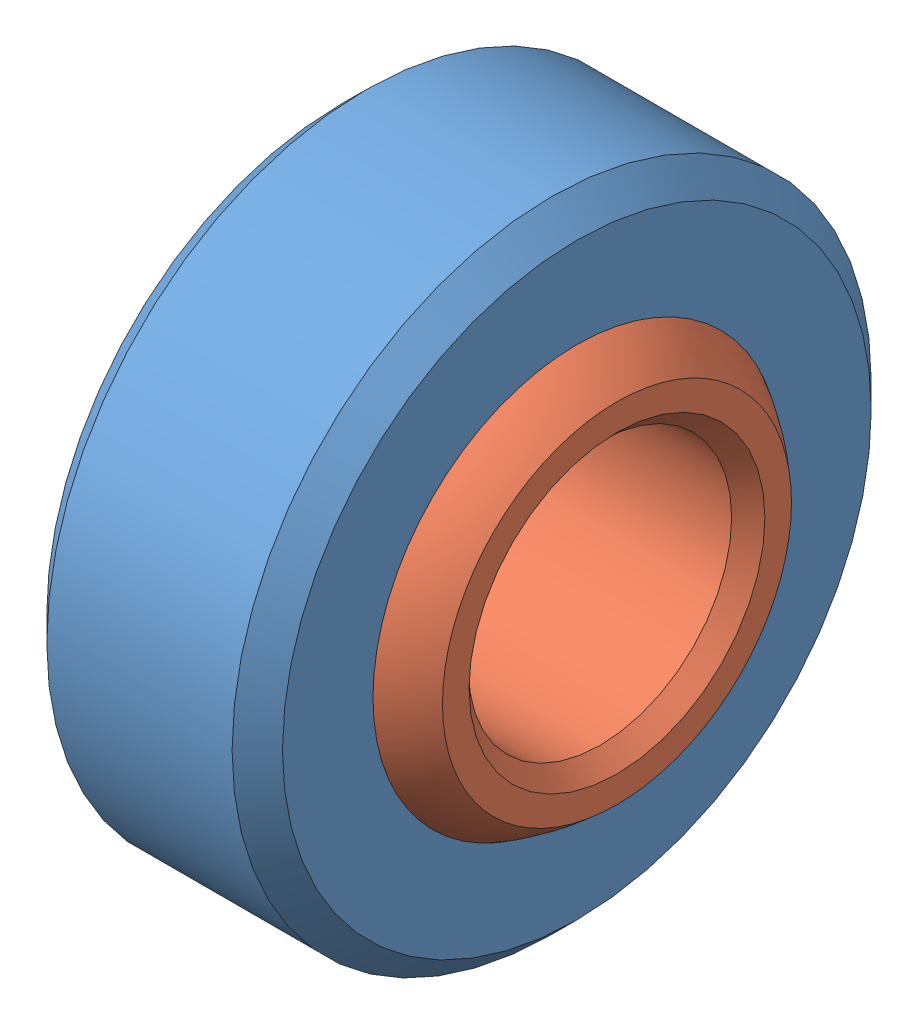
SolidWorks assembly spherical bearing, configuration Default. Lengths in mm.
Overall size (9.53 19.28 19.28).
2 component instances, 2 part files, 1 mates.
Components (placement in the parent):
- spherical bearing outer-1: spherical bearing outer [Default] at origin size (7.11 19.28 19.28)
- spherical bearing inner-1: spherical bearing inner [Default] at origin size (9.53 14.2 14.2)
Mates (geometry in assembly coordinates):
- Concentric1: concentric: sphere of spherical bearing outer-1; sphere of spherical bearing inner-1
